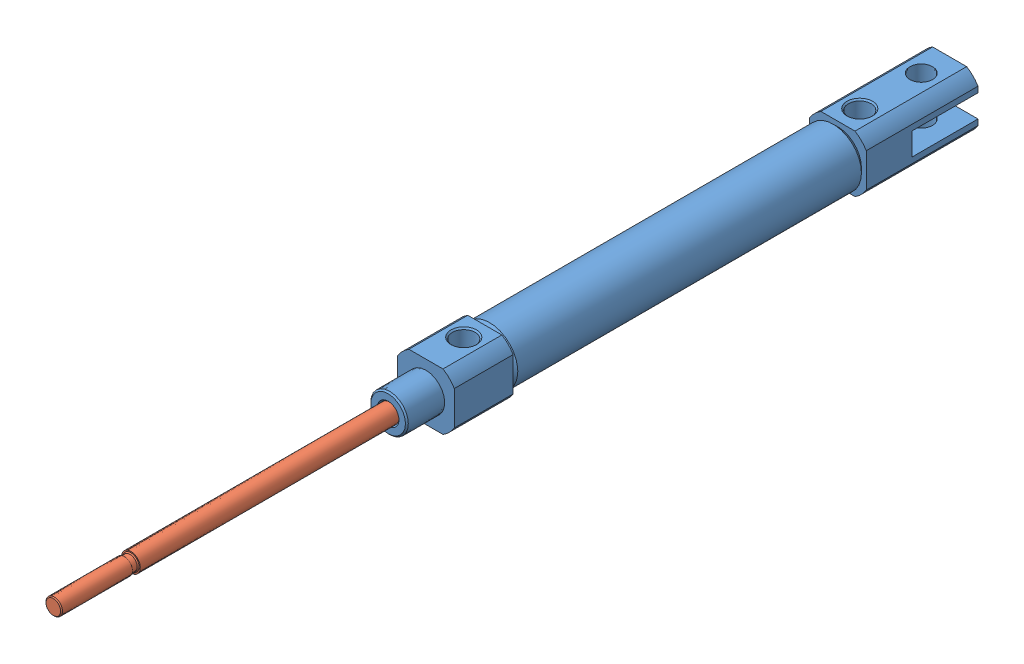
SolidWorks assembly NCJ2D10, configuration Default. Lengths in mm.
Overall size (12.84 12.84 189.54).
2 component instances, 2 part files, 2 mates.
Components (placement in the parent):
- NCJ2D10-200_NCJ2-Body-1: NCJ2D10-200_NCJ2-Body [10D] at (87.147 71.1328 63.9017) size (12 12 118.74)
- NCJ2D10-200_NCJ2-Rod-1: NCJ2D10-200_NCJ2-Rod [10] at (87.147 71.1328 89.3017) x (-0.938292 -0.345845 0) z (0 0 1) size (10 10 105.69)
Mates (geometry in assembly coordinates):
- Concentric1: concentric anti-aligned: cylinder of NCJ2D10-200_NCJ2-Body-1 through (87.147 71.1328 30.3449) axis (0 0 1) radius 2; cylinder of NCJ2D10-200_NCJ2-Rod-1 through (87.147 71.1328 198.1436) axis (0 0 -1) radius 2
- LimitDistance1: limit distance = 50.8 mm anti-aligned: plane of NCJ2D10-200_NCJ2-Rod-1 through (87.147 71.1328 86.8017) normal (0 0 -1); plane of NCJ2D10-200_NCJ2-Body-1 through (87.147 71.1328 36.0017) normal (0 0 1)
